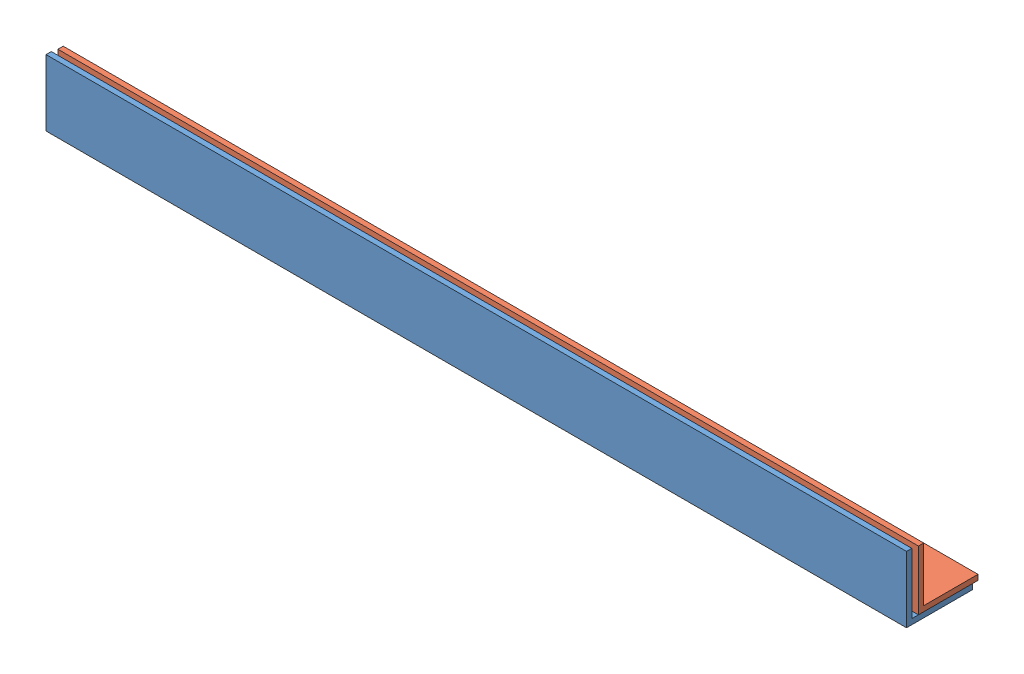
SolidWorks assembly Сборка2, configuration По умолчанию. Lengths in mm.
Overall size (650 50 54).
2 component instances, 2 part files, 3 mates.
Components (placement in the parent):
- Уголок50650-1: Уголок50650 [По умолчанию] at origin size (650 50 50)
- Уголок45650-1: Уголок45650 [По умолчанию] at (0 4 -9) size (650 45 45)
Mates (geometry in assembly coordinates):
- Совпадение4: coincident: plane of Уголок50650-1 through (650 4 0) normal (0 1 0); plane of Уголок45650-1 through (650 4 -22.8694) normal (0 -1 0)
- Совпадение5: coincident: plane of Уголок50650-1 through (650 0 0) normal (1 0 0); plane of Уголок45650-1 through (650 4 -22.8694) normal (1 0 0)
- Расстояние1: distance = 5 mm anti-aligned: plane of Уголок45650-1 through (650 49 -9) normal (0 0 1); plane of Уголок50650-1 through (650 50 -4) normal (0 0 -1)
